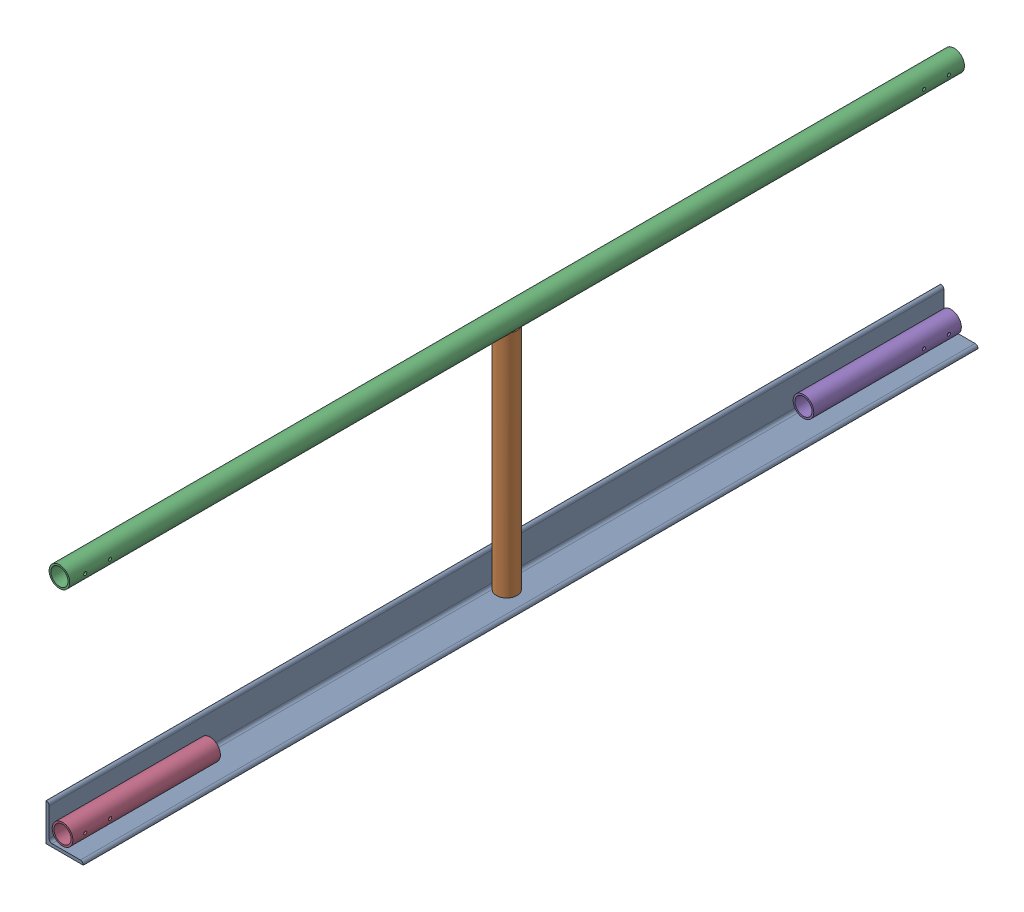
SolidWorks assembly FE-00005_ASM, configuration Default. Lengths in mm.
Overall size (76.2 507.65 1828.8).
5 component instances, 4 part files, 0 mates.
Components (placement in the parent):
- FE-00005-01-1: FE-00005-01 [Default] at origin size (76.2 76.2 1828.8)
- FE-00005-03-1: FE-00005-03 [Default] at (27.432 6.35 914.4) size (42.16 471.23 42.16)
- FE-00005-04-1: FE-00005-04 [Default] at (27.432 486.5688 0) size (42.16 42.16 1828.8)
- FE-00005-02-1: FE-00005-02 [Default] at (27.432 27.432 1520.825) size (42.16 42.16 301.62)
- FE-00005-02-2: FE-00005-02 [Default] at (27.432 27.432 307.975) x (1 0 0) z (0 0 -1) size (42.16 42.16 301.62)
